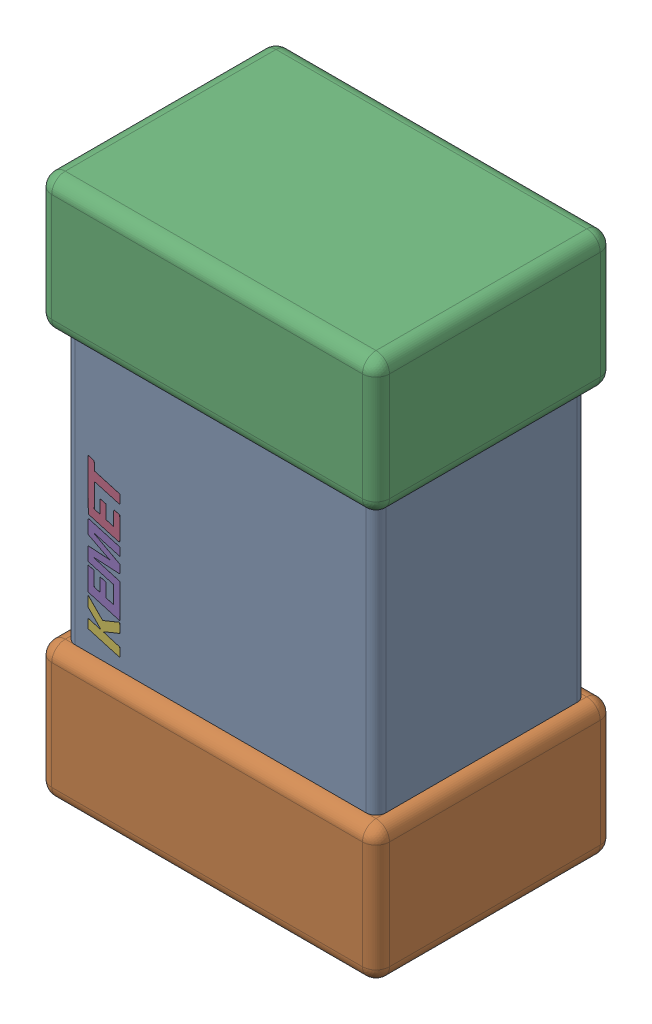
SolidWorks assembly C9.step, configuration Default. Lengths in mm.
Overall size (1.25 2 0.88).
3 component instances, 3 part files, 0 mates.
Components (placement in the parent):
- Cap_KEMET_C0805C472J3HAC_eec.step-1: Cap_KEMET_C0805C472J3HAC_eec.step [Default] at (46.946 65.924 0) x (0 1 0) z (0 0 1) size (1 1.15 0.78)
- Cap_KEMET_C0805C472J3HAC_eec-7.step-1: Cap_KEMET_C0805C472J3HAC_eec-7.step [Default] at (46.946 65.924 0) x (0 1 0) z (0 0 1) size (2 1.25 0.88)
- Cap_KEMET_C0805C472J3HAC_eec-8.step-1: Cap_KEMET_C0805C472J3HAC_eec-8.step [Default] at (46.946 65.924 0) x (0 1 0) z (0 0 1) size (0.59 0.12 0)
